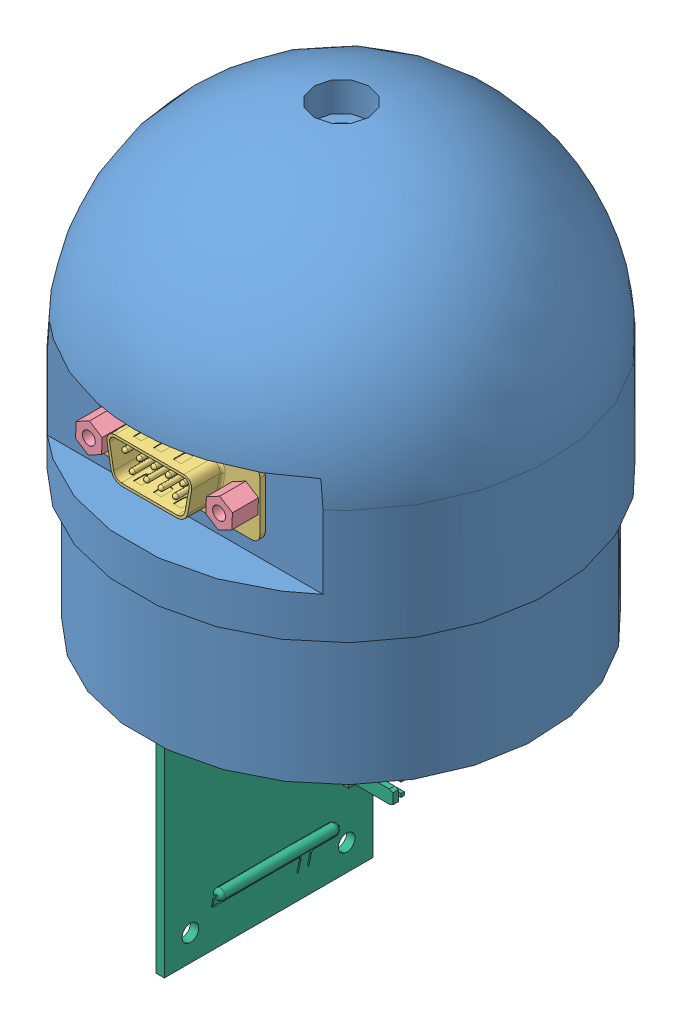
SolidWorks assembly Ftx_Eclairage, configuration Défaut. Lengths in mm.
Overall size (80 142.65 80).
7 component instances, 6 part files, 15 mates.
Components (placement in the parent):
- Ftx_EclairageTete-1: Ftx_EclairageTete [Défaut] at (-43.8717 -8.2632 0) size (80 86.65 80)
- Batterie-1: Batterie [Défaut] at (-26.3717 59.7368 21) x (0 -1 0) z (1 0 0) size (64 42 6.5)
- DB9_Male-1: DB9_Male [Défaut] at (-43.8685 34.2368 30.4953) size (30.73 12.55 15.01)
- EntretoiseHexa-1: EntretoiseHexa [Défaut] at (-56.3717 34.2368 30.9906) x (-0.996128 0.08791 0) z (0.08791 0.996128 0) size (5.14 10 5.77)
- EntretoiseHexa-2: EntretoiseHexa [Défaut] at (-31.3717 34.2368 30.9906) x (-0.996128 0.08791 0) z (0.08791 0.996128 0) size (5.14 10 5.77)
- Vis_M4 x 16-Plastique-1: Vis_M4 x 16-Plastique [Défaut] at (-59.4717 12.7368 -14) x (0 -0.568682 0.822557) z (1 0 0) size (4.62 4.02 16.14)
- CarteECLAI-YC-3: CarteECLAI-YC [Défaut] at (-58.6717 15.2516 9.2326) x (0 1 0) z (-1 0 0) size (121 40 19.3)
Mates (geometry in assembly coordinates):
- Coïncidente3: coincident anti-aligned: plane of Ftx_EclairageTete-1 through (-19.8717 59.7368 22) normal (-1 0 0); plane of Batterie-1 through (-19.8717 59.7368 -21) normal (1 0 0)
- Coïncidente5: coincident anti-aligned: plane of Ftx_EclairageTete-1 through (-57.8717 59.7368 20.5) normal (0 -1 0); plane of Batterie-1 through (-19.8717 59.7368 21) normal (0 1 0)
- Coaxiale5: concentric aligned: circle of Ftx_EclairageTete-1; circle of DB9_Male-1
- Parallèle2: parallel anti-aligned: line of Ftx_EclairageTete-1 through (-17.891 43.7368 30) axis (-1 0 0); line of DB9_Male-1 through (-57.7115 40.5106 30.9906) axis (1 0 0)
- Coïncidente7: coincident anti-aligned: plane of Ftx_EclairageTete-1 through (-81.8717 43.7368 30) normal (0 0 1); plane of DB9_Male-1 through (-52.1978 28.7631 30) normal (0 0 -1)
- Coaxiale6: concentric aligned: cylinder of Ftx_EclairageTete-1 through (-56.3717 34.2368 30) axis (0 0 1) radius 1.025; cylinder of EntretoiseHexa-1 through (-56.3717 34.2368 25.9906) axis (0 0 1) radius 1.25
- Coïncidente8: coincident anti-aligned: plane of DB9_Male-1 through (-30.0255 38.9866 30.9906) normal (0 0 1); plane of EntretoiseHexa-1 through (-58.8151 35.774 30.9906) normal (0 0 -1)
- Coïncidente9: coincident anti-aligned: plane of DB9_Male-1 through (-30.0255 38.9866 30.9906) normal (0 0 1); plane of EntretoiseHexa-2 through (-33.8151 35.774 30.9906) normal (0 0 -1)
- Coaxiale7: concentric aligned: cylinder of Ftx_EclairageTete-1 through (-31.3717 34.2368 30) axis (0 0 1) radius 1.025; cylinder of EntretoiseHexa-2 through (-31.3717 34.2368 25.9906) axis (0 0 1) radius 1.25
- Coaxiale8: concentric aligned: cylinder of Ftx_EclairageTete-1 through (-60.8717 12.7368 -14) axis (1 0 0) radius 2.1; circle of Vis_M4 x 16-Plastique-1
- Coïncidente10: coincident anti-aligned: plane of Ftx_EclairageTete-1 through (-57.8717 59.7368 18) normal (-1 0 0); plane of CarteECLAI-YC-3 through (-57.8717 -64.2632 -20) normal (1 0 0)
- Coaxiale9: concentric aligned: circle of Ftx_EclairageTete-1; circle of CarteECLAI-YC-3
- Parallèle3: parallel anti-aligned: plane of Ftx_EclairageTete-1 through (-57.8717 59.7368 20.5) normal (0 0 -1); plane of CarteECLAI-YC-3 through (-59.4717 -64.2632 20) normal (0 0 1)
- Distance2: distance = 1 mm anti-aligned: plane of Ftx_EclairageTete-1 through (-27.8717 59.7368 22) normal (0 0 -1); plane of Batterie-1 through (-19.8717 59.7368 21) normal (0 0 1)
- Coïncidente13: coincident aligned: circle of Vis_M4 x 16-Plastique-1; plane of CarteECLAI-YC-3 through (-59.4717 -64.2632 -20) normal (-1 0 0)
